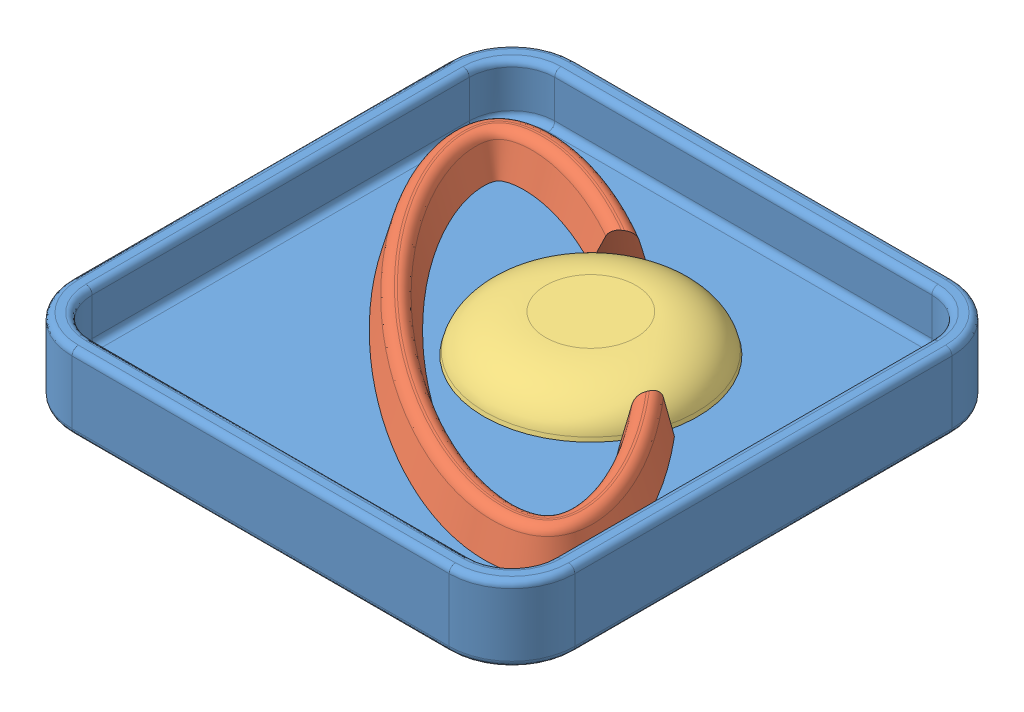
SolidWorks assembly Assem4, configuration Default. Lengths in mm.
Overall size (40 6 40).
3 component instances, 3 part files, 2 mates.
Components (placement in the parent):
- Tile-1: Tile [Default] at (9.6336 15.7672 34.9302) size (40 6 40)
- BlackHole-1: BlackHole [Default] at (9.6332 17.7672 32.2804) size (38.32 3.6 34.74)
- BlackHole_B-1: BlackHole_B [Default] at (11.7014 17.7672 30.7267) size (17 3.02 17)
Mates (geometry in assembly coordinates):
- Coincident4: coincident anti-aligned: plane of Tile-1 through (-5.3664 17.7672 49.9302) normal (0 1 0); plane of BlackHole-1 through (9.6332 17.7672 34.0447) normal (0 -1 0)
- Coincident6: coincident anti-aligned: plane of Tile-1 through (-5.3664 17.7672 49.9302) normal (0 1 0); plane of BlackHole_B-1 through (11.7014 17.7672 30.7267) normal (0 -1 0)
